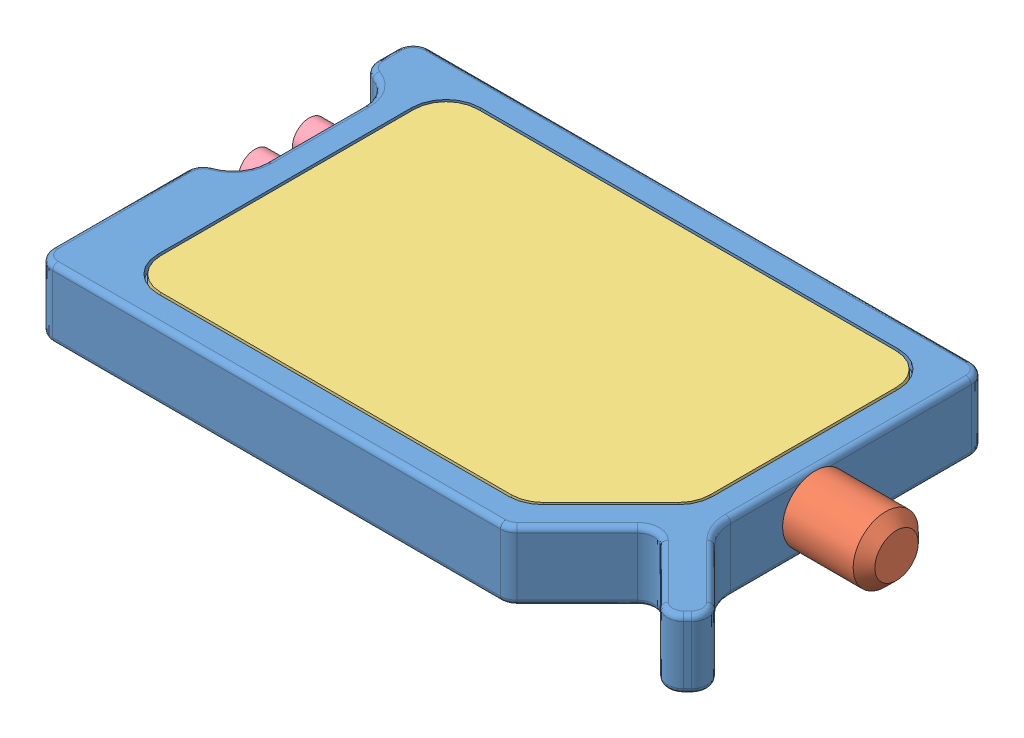
SolidWorks assembly Assem1, configuration Default. Lengths in mm.
Overall size (120.86 16.34 69.43).
5 component instances, 5 part files, 11 mates.
Components (placement in the parent):
- pcb-1: pcb [Default] at (-12.1548 0.0441 6.384) size (100 1.6 60) (hidden)
- top-1: top [Default] at (-24.2849 -46.8134 1.1789) size (118.76 12.7 69.43)
- knob-1: knob [Default] at (21.5729 -46.8134 -1.7724) x (0 -0.490048 -0.871696) z (0 -0.871696 0.490048) size (12 15 12)
- Part5^Assem1-1: Part5^Assem1 [Default] at (-24.2849 -41.9634 1.1789) x (1 0 0) z (0 1 0) size (88.8 58.43 1.5) (virtual)
- Part6^Assem1-1: Part6^Assem1 [Default] at (-78.2305 -46.8134 1.1789) x (0 0 1) z (-1 0 0) size (16.21 6.21 6.05) (virtual)
Mates (geometry in assembly coordinates):
- Coincident1: coincident anti-aligned: plane of top-1 through (21.5729 -46.8134 16.8042) normal (1 0 0); plane of knob-1 through (21.5729 -46.8134 -1.7724) normal (-1 0 0)
- InPlace1: in place: plane of ? through (-6.2644 4.564 2.3897) normal (0 1 0); plane of ? through (0 4.564 0) normal (0 1 0); moOrthogonalPlaneRef_w of ? through (-6.2644 4.564 2.3897) normal (0 1 0); plane of ? through (0 4.564 0) normal (0 0 -1); plane of ? through (-6.2644 4.564 2.3897) normal (0 1 0); line of ? through (-55 0 4.564) axis (0 1 0); plane of top-1 through (-24.2849 -41.9634 1.1789) normal (0 1 0); unknown of Part5^Assem1-1
- Coincident2: coincident aligned: plane of top-1; plane of Part5^Assem1-1
- Coincident3: coincident aligned: moOrthogonalPlaneRef_w of top-1 through (-24.2849 -41.9634 1.1789) normal (0 0 -1); plane of Part5^Assem1-1 through (-24.2849 -41.9634 1.1789) normal (0 0 -1)
- Coincident4: coincident anti-aligned: moOrthogonalPlaneRef_w of top-1 through (-24.2849 -41.9634 1.1789) normal (-1 0 0); plane of Part5^Assem1-1
- InPlace2: in place: plane of ? through (-60.21 -0.286 -17.1663) normal (-1 0 0); plane of ? through (-60.21 0 0) normal (-1 0 0); plane of ? through (-60.21 -0.286 -17.1663) normal (-1 0 0); line of ? through (-55 -60.21 0) axis (0 0 1); plane of ? through (-60.21 -0.286 -17.1663) normal (-1 0 0); plane of ? through (-60.21 0 0) normal (0 0 1); plane of top-1 through (-78.2305 -46.8134 -18.3771) normal (-1 0 0); unknown of Part6^Assem1-1
- Coincident5: coincident aligned: plane of top-1; plane of Part6^Assem1-1
- Coincident6: coincident aligned: moOrthogonalPlaneRef_w of top-1 through (-78.2305 -46.8134 1.1789) normal (0 1 0); plane of Part6^Assem1-1
- Coincident7: coincident anti-aligned: moOrthogonalPlaneRef_w of top-1 through (-78.2305 -46.8134 1.1789) normal (0 0 -1); plane of Part6^Assem1-1 through (-78.2305 -46.8134 1.1789) normal (0 0 1)
- Parallel3: parallel anti-aligned: line of top-1 through (18.5729 -40.4634 -32.5383) axis (-1 0 0); line of knob-1 through (20.8229 -46.8134 -1.7724) axis (1 0 0)
- Coincident9: coincident: plane of top-1 through (-24.2849 -46.8134 1.1789) normal (0 1 0); line of knob-1 through (20.8229 -46.8134 -1.7724) axis (1 0 0)
